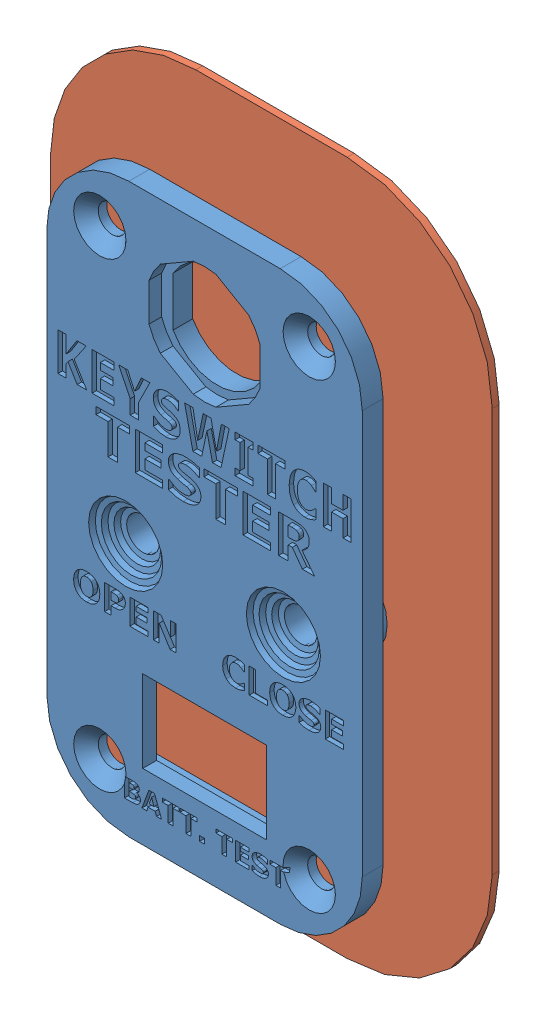
SolidWorks assembly panelWith3dPrintingHelpers, configuration Default. Lengths in mm.
Overall size (70 110 11.83).
2 component instances, 2 part files, 2 mates.
Components (placement in the parent):
- keyswitchTester.box.panel-1: keyswitchTester.box.panel [Default] at origin size (50 90 9.73)
- raft^panelWith3dPrintingHelpers-1: raft^panelWith3dPrintingHelpers [Default] at origin size (70 110 1.1) (virtual)
Mates (geometry in assembly coordinates):
- Coincident1: coordinate: point of ?
- Coincident2: coordinate: unknown of ?
